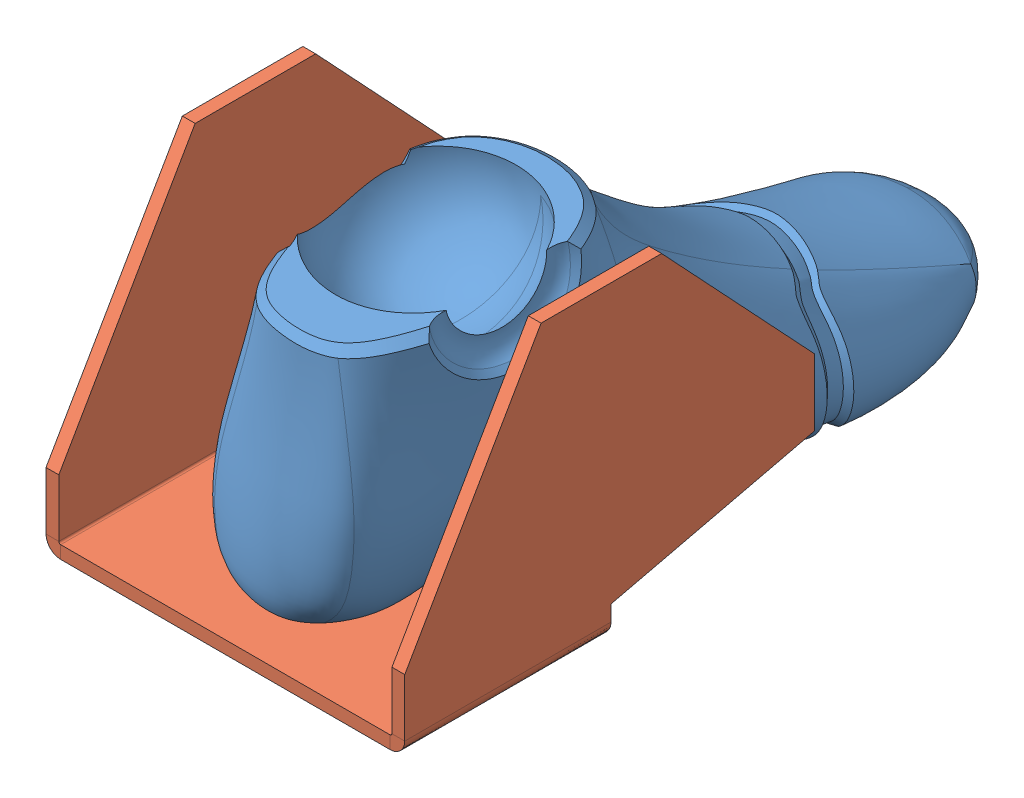
SolidWorks assembly FootL-Rev1, configuration Default. Lengths in mm.
Overall size (230.39 191.19 289.78).
2 component instances, 2 part files, 1 mates.
Components (placement in the parent):
- Foot_L-1: Foot_L [Default] at (82.3166 0 186.7027) x (-0.310622 0 0.950534) z (0 1 0) size (250.8 160.43 191.19)
- Part1^FootL-Rev1-1: Part1^FootL-Rev1 [Default] at (24.5554 -2.5597 99.2736) x (-1 0 0) z (0 0 -1) size (140 120.4 160) (virtual)
Mates (geometry in assembly coordinates):
- Coincident1: coincident anti-aligned: plane of Foot_L-1 through (8.8465 0 -88.9233) normal (0 -1 0)
